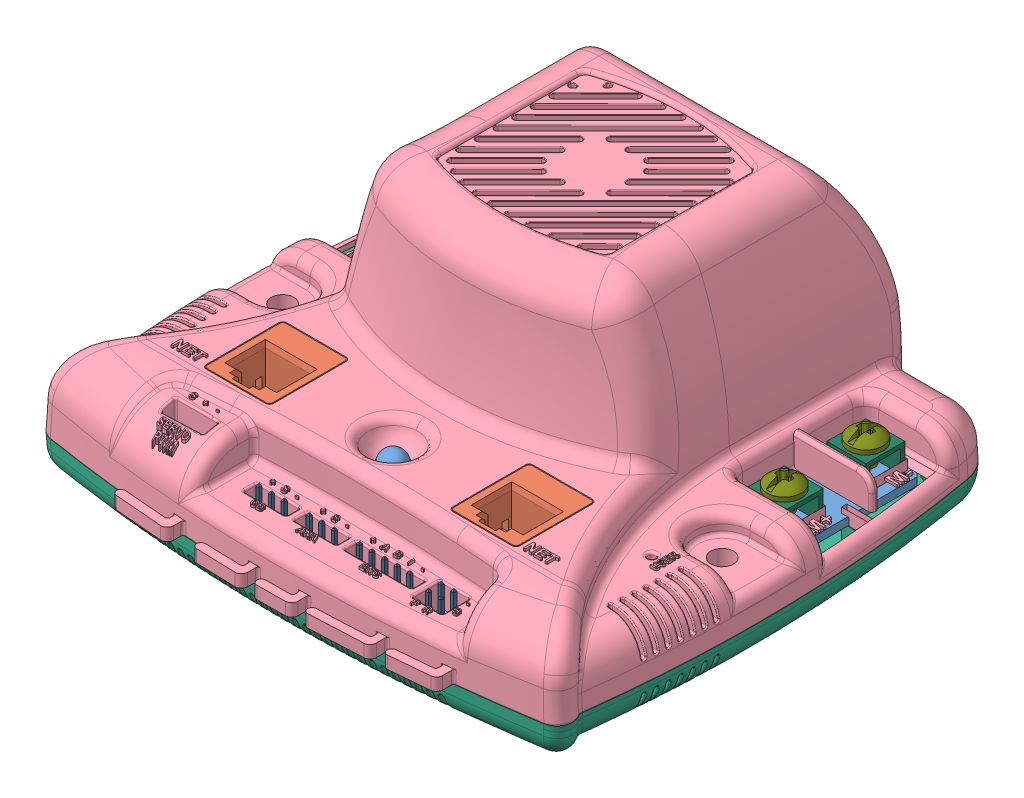
SolidWorks assembly jaguar, configuration Default. Lengths in mm.
Overall size (108.73 52.96 100.91).
89 component instances, 25 part files, 0 mates.
Components (placement in the parent):
- A-LM-0608-1_PCB_ASM-1: A-LM-0608-1_PCB_ASM [Default] at origin size (88.9 41.9 85.73)
  - C-JAGUAR-PCB-BOARD-1: C-JAGUAR-PCB-BOARD [Default] at origin size (88.9 1.59 85.73)
  - C-L9_RJ11-424106314-1: C-L9_RJ11-424106314 [Default] at (24.9174 8.0645 20.84) x (0 0 -1) z (1 0 0) size (15.88 18.87 15.75)
  - C-L9_RJ11-424106314-2: C-L9_RJ11-424106314 [Default] at (-24.9174 8.0645 20.84) x (0 0 -1) z (1 0 0) size (15.88 18.87 15.75)
  - C-L2-CAPACITOR-1: C-L2-CAPACITOR [Default] at (-0.0004 0 -17.78) size (20 20 20)
  - C-L10_FTS-105-02-X-DV-SA_ANY_ASM-1: C-L10_FTS-105-02-X-DV-SA_ANY_ASM [Default] at (36.0682 -2.8686 -7.8738) x (0 0 1) z (1 0 0) size (6.35 6.3 3.41)
    - T-1S15_-02_FTSH-DV_ANY-1: T-1S15_-02_FTSH-DV_ANY [Default] at (-2.54 -0.635 -0.635) x (0 0 -1) z (1 0 0) size (0.41 6.3 0.41)
    - T-1S15_-02_FTSH-DV_ANY_AF0-1: T-1S15_-02_FTSH-DV_ANY_AF0 [Default] at (2.54 -0.635 0.635) x (0 0 1) z (-1 0 0) size (0.41 6.3 0.41)
    - T-1S15_-02_FTSH-DV_ANY-2: T-1S15_-02_FTSH-DV_ANY [Default] at (-1.27 -0.635 -0.635) x (0 0 -1) z (1 0 0) size (0.41 6.3 0.41)
    - T-1S15_-02_FTSH-DV_ANY-3: T-1S15_-02_FTSH-DV_ANY [Default] at (1.27 -0.635 -0.635) x (0 0 -1) z (1 0 0) size (0.41 6.3 0.41)
    - T-1S15_-02_FTSH-DV_ANY-4: T-1S15_-02_FTSH-DV_ANY [Default] at (0 -0.635 -0.635) x (0 0 -1) z (1 0 0) size (0.41 6.3 0.41)
    - T-1S15_-02_FTSH-DV_ANY-5: T-1S15_-02_FTSH-DV_ANY [Default] at (2.54 -0.635 -0.635) x (0 0 -1) z (1 0 0) size (0.41 6.3 0.41)
    - T-1S15_-02_FTSH-DV_ANY-6: T-1S15_-02_FTSH-DV_ANY [Default] at (1.27 -0.635 0.635) x (0 0 1) z (-1 0 0) size (0.41 6.3 0.41)
    - T-1S15_-02_FTSH-DV_ANY-7: T-1S15_-02_FTSH-DV_ANY [Default] at (0 -0.635 0.635) x (0 0 1) z (-1 0 0) size (0.41 6.3 0.41)
    - T-1S15_-02_FTSH-DV_ANY-8: T-1S15_-02_FTSH-DV_ANY [Default] at (-2.54 -0.635 0.635) x (0 0 1) z (-1 0 0) size (0.41 6.3 0.41)
    - FTS-X-DV_FORMULA_ANY_AF0-1: FTS-X-DV_FORMULA_ANY_AF0 [Default] at origin size (6.35 1 3.41)
    - T-1S15_-02_FTSH-DV_ANY-9: T-1S15_-02_FTSH-DV_ANY [Default] at (-1.27 -0.635 0.635) x (0 0 1) z (-1 0 0) size (0.41 6.3 0.41)
  - L11-SSW-104-01-X-S_ASM-1: L11-SSW-104-01-X-S_ASM [Default] at (-27.6182 0 35.6196) size (8.12 11.05 2.5)
    - SSW-XX-X-1: SSW-XX-X [Default] at origin size (8.12 8.51 2.5)
    - C-08-X-1: C-08-X [Default] at (-1.27 0.508 1.2192) size (1.96 9.53 0.41)
    - C-08-X-2: C-08-X [Default] at (1.27 0.508 1.2192) size (1.96 9.53 0.41)
    - C-08-X-3: C-08-X [Default] at (3.81 0.508 1.2192) size (1.96 9.53 0.41)
  - C-L13-1X3_HEADER_ASM-1: C-L13-1X3_HEADER_ASM [Default] at (-3.5052 1.524 36.8173) size (7.62 10.92 2.54)
    - C-HEADER-3PIN-BODY-1: C-HEADER-3PIN-BODY [Default] at origin size (7.62 2.54 2.54)
    - C-T-HEADER-PIN-1: C-T-HEADER-PIN [Default] at (-6.35 -2.0599 0) x (0 0 1) z (-1 0 0) size (0.64 10.92 0.64)
    - C-T-HEADER-PIN-2: C-T-HEADER-PIN [Default] at (-3.81 -2.0599 0) x (0 0 1) z (-1 0 0) size (0.64 10.92 0.64)
    - C-T-HEADER-PIN-3: C-T-HEADER-PIN [Default] at (-8.89 -2.0599 0) x (0 0 1) z (-1 0 0) size (0.64 10.92 0.64)
  - C-L13-1X3_HEADER_ASM-2: C-L13-1X3_HEADER_ASM [Default] at (6.6548 1.524 36.8173) size (7.62 10.92 2.54)
    - C-HEADER-3PIN-BODY-1: C-HEADER-3PIN-BODY [Default] at origin size (7.62 2.54 2.54)
    - C-T-HEADER-PIN-1: C-T-HEADER-PIN [Default] at (-6.35 -2.0599 0) x (0 0 1) z (-1 0 0) size (0.64 10.92 0.64)
    - C-T-HEADER-PIN-2: C-T-HEADER-PIN [Default] at (-3.81 -2.0599 0) x (0 0 1) z (-1 0 0) size (0.64 10.92 0.64)
    - C-T-HEADER-PIN-3: C-T-HEADER-PIN [Default] at (-8.89 -2.0599 0) x (0 0 1) z (-1 0 0) size (0.64 10.92 0.64)
  - C-L12-1X5_HEADER_ASM-1: C-L12-1X5_HEADER_ASM [Default] at (16.8148 1.524 36.8173) size (12.7 10.92 2.54)
    - C-T-HEADER-PIN-1: C-T-HEADER-PIN [Default] at (-6.35 -2.0599 0) x (0 0 1) z (-1 0 0) size (0.64 10.92 0.64)
    - C-T-HEADER-PIN-2: C-T-HEADER-PIN [Default] at (-3.81 -2.0599 0) x (0 0 1) z (-1 0 0) size (0.64 10.92 0.64)
    - C-T-HEADER-PIN-3: C-T-HEADER-PIN [Default] at (1.27 -2.0599 0) x (0 0 1) z (-1 0 0) size (0.64 10.92 0.64)
    - C-T-HEADER-PIN-4: C-T-HEADER-PIN [Default] at (-8.89 -2.0599 0) x (0 0 1) z (-1 0 0) size (0.64 10.92 0.64)
    - C-T-HEADER-PIN-5: C-T-HEADER-PIN [Default] at (-1.27 -2.0599 0) x (0 0 1) z (-1 0 0) size (0.64 10.92 0.64)
    - C-TSW-XX-S_FORMULA_ANY-5-1: C-TSW-XX-S_FORMULA_ANY-5 [Default] at origin size (12.7 2.54 2.54)
  - C-U1_LUMINARY-CHIP-1: C-U1_LUMINARY-CHIP [Default] at (9.887 0 22.86) size (12 1.45 12)
  - C-BUTTON-SWITCH_ASM-1: C-BUTTON-SWITCH_ASM [Default] at (40.8559 0 10.668) size (6 5 6)
    - C-BS-SWITCH-BASE-1: C-BS-SWITCH-BASE [Default] at origin size (6 4 6)
    - C-BS-EXTENSION-1: C-BS-EXTENSION [Default] at origin size (3.5 1.9 3.5)
  - C-SCREW-TERMINAL-7701_ASM-1: C-SCREW-TERMINAL-7701_ASM [Default] at (39.2172 -5.0038 -17.7792) size (7.87 10.19 7.87)
    - C-ST-7701-BASE-1: C-ST-7701-BASE [Default] at origin size (7.87 7.76 7.87)
    - 6-PH-SCREW-25-1: 6-PH-SCREW-25 [Default] at (0 11.176 0) size (6.86 7.18 6.86)
  - C-SCREW-TERMINAL-7701_ASM-2: C-SCREW-TERMINAL-7701_ASM [Default] at (39.2172 -5.0038 -34.2892) size (7.87 10.19 7.87)
    - C-ST-7701-BASE-1: C-ST-7701-BASE [Default] at origin size (7.87 7.76 7.87)
    - 6-PH-SCREW-25-1: 6-PH-SCREW-25 [Default] at (0 11.176 0) size (6.86 7.18 6.86)
  - C-SCREW-TERMINAL-7701_ASM-3: C-SCREW-TERMINAL-7701_ASM [Default] at (-39.2172 -5.0038 -34.2892) size (7.87 10.19 7.87)
    - C-ST-7701-BASE-1: C-ST-7701-BASE [Default] at origin size (7.87 7.76 7.87)
    - 6-PH-SCREW-25-1: 6-PH-SCREW-25 [Default] at (0 11.176 0) size (6.86 7.18 6.86)
  - C-SCREW-TERMINAL-7701_ASM-4: C-SCREW-TERMINAL-7701_ASM [Default] at (-39.2172 -5.0038 -17.7792) size (7.87 10.19 7.87)
    - C-ST-7701-BASE-1: C-ST-7701-BASE [Default] at origin size (7.87 7.76 7.87)
    - 6-PH-SCREW-25-1: 6-PH-SCREW-25 [Default] at (0 11.176 0) size (6.86 7.18 6.86)
  - C-Q1-Q12_MOSFET-1: C-Q1-Q12_MOSFET [Default] at (0.2539 4.8006 -35.56) x (1 0 0.000017) z (-0.000017 0 1) size (4.57 20.75 10.36)
  - C-Q1-Q12_MOSFET-2: C-Q1-Q12_MOSFET [Default] at (8.9829 4.8006 -32.9335) x (0.866017 0 0.500015) z (-0.500015 0 0.866017) size (4.57 20.75 10.36)
  - C-Q1-Q12_MOSFET-3: C-Q1-Q12_MOSFET [Default] at (8.7964 4.8006 -2.2451) x (-0.866035 0 0.499983) z (-0.499983 0 -0.866035) size (4.57 20.75 10.36)
  - C-Q1-Q12_MOSFET-4: C-Q1-Q12_MOSFET [Default] at (-0.2547 4.8006 0) x (-1 0 -0.000017) z (0.000017 0 -1) size (4.57 20.75 10.36)
  - C-Q1-Q12_MOSFET-5: C-Q1-Q12_MOSFET [Default] at (-9.1106 4.8006 -2.4995) x (-0.866018 0 -0.500013) z (0.500013 0 -0.866018) size (4.57 20.75 10.36)
  - C-Q1-Q12_MOSFET-6: C-Q1-Q12_MOSFET [Default] at (-8.4161 4.8006 -33.3149) x (0.866034 0 -0.499985) z (0.499985 0 0.866034) size (4.57 20.75 10.36)
  - C-Q1-Q12_MOSFET-7: C-Q1-Q12_MOSFET [Default] at (15.4531 4.8006 -26.8897) x (-0.499985 0 -0.866034) z (0.866034 0 -0.499985) size (4.57 20.75 10.36)
  - C-Q1-Q12_MOSFET-8: C-Q1-Q12_MOSFET [Default] at (17.7796 4.8006 -18.0337) x (0.000017 0 -1) z (1 0 0.000017) size (4.57 20.75 10.36)
  - C-Q1-Q12_MOSFET-9: C-Q1-Q12_MOSFET [Default] at (15.7068 4.8006 -9.1097) x (0.500015 0 -0.866017) z (0.866017 0 0.500015) size (4.57 20.75 10.36)
  - C-Q1-Q12_MOSFET-10: C-Q1-Q12_MOSFET [Default] at (-15.4538 4.8006 -8.6703) x (0.499985 0 0.866034) z (-0.866034 0 0.499985) size (4.57 20.75 10.36)
  - C-Q1-Q12_MOSFET-11: C-Q1-Q12_MOSFET [Default] at (-17.7804 4.8006 -17.5263) x (-0.000017 0 1) z (-1 0 -0.000017) size (4.57 20.75 10.36)
  - C-Q1-Q12_MOSFET-12: C-Q1-Q12_MOSFET [Default] at (-15.7075 4.8006 -26.4503) x (-0.500015 0 0.866017) z (-0.866017 0 -0.500015) size (4.57 20.75 10.36)
  - C-Q1-Q12_MOSFET-13: C-Q1-Q12_MOSFET [Default] at (0.2539 4.8006 -35.56) size (4.57 20.75 10.36)
  - P-LM-0608-1-003_MOSFET-RING-1: P-LM-0608-1-003_MOSFET-RING [Default] at origin size (51.07 7.69 51.07)
  - I15_59-1: I15_59 [Default] at (0 5.8 22.11) size (5.9 13.4 5.84)
  - D4010-1: D4010 [Default] at (-0.0004 25.4 -17.78) x (0.000017 0 -1) z (-1 0 -0.000017) size (40 11.76 40)
  - C-L13-1X2_HEADER_ASM-1: C-L13-1X2_HEADER_ASM [Default] at (32.0548 1.524 35.5473) size (5.08 10.92 2.54)
    - C-HEADER-2PIN-BODY-1: C-HEADER-2PIN-BODY [Default] at origin size (5.08 2.54 2.54)
    - C-T-HEADER-PIN-1: C-T-HEADER-PIN [Default] at (-6.35 -2.0599 0) x (0 0 1) z (-1 0 0) size (0.64 10.92 0.64)
    - C-T-HEADER-PIN-2: C-T-HEADER-PIN [Default] at (-8.89 -2.0599 0) x (0 0 1) z (-1 0 0) size (0.64 10.92 0.64)
  - C-L13-1X2_HEADER_ASM-2: C-L13-1X2_HEADER_ASM [Default] at (32.0548 1.524 38.0873) size (5.08 10.92 2.54)
    - C-HEADER-2PIN-BODY-1: C-HEADER-2PIN-BODY [Default] at origin size (5.08 2.54 2.54)
    - C-T-HEADER-PIN-1: C-T-HEADER-PIN [Default] at (-6.35 -2.0599 0) x (0 0 1) z (-1 0 0) size (0.64 10.92 0.64)
    - C-T-HEADER-PIN-2: C-T-HEADER-PIN [Default] at (-8.89 -2.0599 0) x (0 0 1) z (-1 0 0) size (0.64 10.92 0.64)
- 217-3367-001-1: 217-3367-001 [Default] at origin size (108.73 46.49 100.91)
- 4-PH-SCREW-58-1: 4-PH-SCREW-58 [Default] at (-16.0007 25.4 -1.7803) x (-1 0 0) z (0 0 1) size (5.56 17.84 5.56)
- 217-3367-002-1: 217-3367-002 [Default] at origin size (107.95 8.08 97.61)
- 4-PH-SCREW-5-1: 4-PH-SCREW-5 [Default] at (46.482 -3.7084 36.4715) x (-1 0 0) z (0 0 1) size (5.56 14.66 5.56)
- 4-PH-SCREW-5-2: 4-PH-SCREW-5 [Default] at (43.9521 -3.7084 -44.717) x (-1 0 0) z (0 0 1) size (5.56 14.66 5.56)
- 4-PH-SCREW-5-3: 4-PH-SCREW-5 [Default] at (-43.9521 -3.7084 -44.717) x (-1 0 0) z (0 0 1) size (5.56 14.66 5.56)
- 4-PH-SCREW-5-4: 4-PH-SCREW-5 [Default] at (-46.482 -3.7084 36.4715) x (-1 0 0) z (0 0 1) size (5.56 14.66 5.56)
- 4-PH-SCREW-58-2: 4-PH-SCREW-58 [Default] at (-16.0001 25.4 -33.7803) x (-1 0 0) z (0 0 1) size (5.56 17.84 5.56)
- 4-PH-SCREW-58-3: 4-PH-SCREW-58 [Default] at (15.9999 25.4 -33.7797) x (-1 0 0) z (0 0 1) size (5.56 17.84 5.56)
- 4-PH-SCREW-58-4: 4-PH-SCREW-58 [Default] at (15.9993 25.4 -1.7797) x (-1 0 0) z (0 0 1) size (5.56 17.84 5.56)
